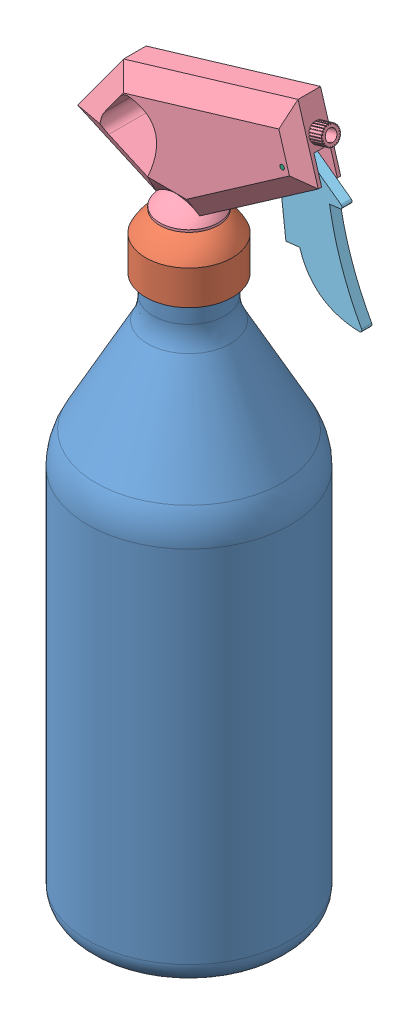
SolidWorks assembly proj_assem, configuration Default. Lengths in mm.
Overall size (124.32 340.73 90).
6 component instances, 6 part files, 7 mates.
Components (placement in the parent):
- proj_container-1: proj_container [Default] at (84.5743 145.7616 194.796) size (90 256.58 90)
- proj_cap-1: proj_cap [Default] at (84.5743 229.4166 194.796) x (-0.381608 0 0.924324) z (-0.924324 0 -0.381608) size (38.5 32 38.5)
- proj_straw-1: proj_straw [Default] at (84.5743 -3.9832 194.796) x (0.186909 0 -0.982377) z (0.982377 0 0.186909) size (7.5 260 7.5)
- proj_nozzle-2: proj_nozzle [Default] at (84.5743 254.0141 194.796) x (-0.00134 0 0.999999) z (-0.999999 0 -0.00134) size (26 71.33 108.98)
- proj_trigger-4: proj_trigger [Default] at (137.1823 304.2493 192.6165) x (-0.00134 0 0.999999) z (-0.993283 -0.115701 -0.001331) size (5 60 52.15)
- proj_hinge-1: proj_hinge [Default] at (136.044 300.7205 184.865) x (-0.00134 0 0.999999) z (-0.997147 0.07547 -0.001336) size (20 3.6 3.6)
Mates (geometry in assembly coordinates):
- Concentric1: concentric aligned: cylinder of proj_container-1 through (84.5743 241.1838 194.796) axis (0 -1 0) radius 15.5; cylinder of proj_cap-1 through (84.5743 244.6666 194.796) axis (0 -1 0) radius 18.75
- Concentric2: concentric anti-aligned: cylinder of proj_cap-1 through (84.5743 261.4166 194.796) axis (0 -1 0) radius 2.5; cylinder of proj_straw-1 through (84.5743 -3.9832 194.796) axis (0 1 0) radius 2.6
- Coincident1: coincident anti-aligned: circle of proj_cap-1; plane of proj_straw-1 through (84.5743 256.0168 194.796) normal (0 1 0)
- Coincident8: coincident anti-aligned: circle of proj_nozzle-2; circle of proj_hinge-1
- Hinge6: hinge anti-aligned: cylinder of proj_trigger-4 through (136.0336 300.7205 192.615) axis (-0.00134 0 0.999999) radius 1; cylinder of proj_hinge-1 through (136.034 300.7205 192.365) axis (-0.00134 0 0.999999) radius 1; plane of proj_hinge-1 through (136.034 300.7205 192.365) normal (-0.00134 0 0.999999); plane of proj_trigger-4 through (136.034 300.7205 192.365) normal (0.00134 0 -0.999999)
- Coincident12: coincident aligned: circle of proj_cap-1; circle of proj_nozzle-2
- Concentric8: concentric aligned: cylinder of proj_container-1 through (84.5743 228.1838 194.796) axis (0 1 0) radius 16.0133; circle of proj_cap-1
